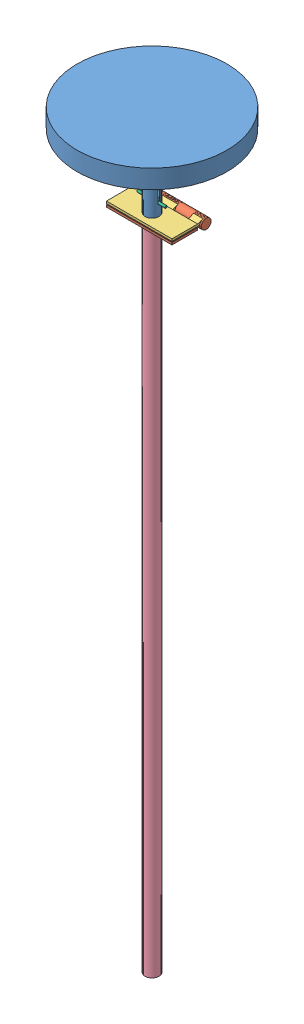
SolidWorks assembly Folding Steering Wheel, configuration Default. Lengths in mm.
Overall size (203.2 312.4 984.57).
6 component instances, 6 part files, 16 mates.
Components (placement in the parent):
- Mock Steering Wheel-1: Mock Steering Wheel [Default] at (27.4075 132.5013 163.5585)
- Door Hinge (2)-1: Door Hinge (2) [1494A11] at (27.4075 30.3171 136.571) x (-1 0 0) z (0 0 -1)
- Opposite Hinge-1: Opposite Hinge [Default] at (71.8575 30.3171 155.4226) x (0 0 -1) z (-1 0 0)
- Mock Steering Shaft-1: Mock Steering Shaft [Default] at (27.4075 -859.2671 163.5585) x (-0.950128 0 0.311862) z (-0.311862 0 -0.950128)
- Dowel-1: Dowel [Default] at (27.4075 8.6763 163.5585) x (1 0 0) z (0 1 0)
- Pull Pin-1: Pull Pin [Default] at (8.3575 49.9513 163.5585) x (1 0 0) z (0 0.325488 -0.945546)
Mates (geometry in assembly coordinates):
- Concentric2: concentric anti-aligned: cylinder of Door Hinge (2)-1 through (2.8414 30.3171 136.571) axis (-1 0 0) radius 6.7469; cylinder of Opposite Hinge-1 through (-17.0425 30.3171 136.571) axis (1 0 0) radius 3.3734
- Coincident9: coincident anti-aligned: circle of Door Hinge (2)-1; plane of Opposite Hinge-1 through (71.8575 30.3171 136.571) normal (1 0 0)
- Coincident10: coincident anti-aligned: circle of Mock Steering Wheel-1; circle of Opposite Hinge-1
- Parallel3: parallel aligned: plane of Opposite Hinge-1 through (71.8575 30.3171 136.571) normal (1 0 0)
- Coincident13: coincident anti-aligned: cylinder of Mock Steering Wheel-1 through (27.4075 119.8013 61.9585) axis (0 0 1) radius 2.3813; circle of 92620A544_Zinc Yellow-Chromate Plated Hex Head Screw-1
- Tangent1: tangent anti-aligned: cylinder of Mock Steering Wheel-1 through (27.4075 30.9013 163.5585) axis (0 1 0) radius 9.525; plane of 92620A544_Zinc Yellow-Chromate Plated Hex Head Screw-1 through (27.4075 94.4671 173.0835) normal (0 0 -1)
- Concentric3: concentric: cylinder of Mock Steering Wheel-1 through (27.4075 119.8013 61.9585) axis (0 0 1) radius 2.3813; circle of 92620A203_Zinc Yellow-Chromate Plated Hex Head Screw(1)-1
- Tangent2: tangent anti-aligned: cylinder of Mock Steering Wheel-1 through (27.4075 30.9013 163.5585) axis (0 1 0) radius 9.525; plane of 92620A203_Zinc Yellow-Chromate Plated Hex Head Screw(1)-1 through (31.9903 88.0513 173.0835) normal (0 0 -1)
- Concentric7: concentric anti-aligned: cylinder of Mock Steering Wheel-1 through (27.4075 30.9013 163.5585) axis (0 1 0) radius 8.636; cylinder of Dowel-1 through (27.4075 58.9854 163.5585) axis (0 -1 0) radius 8.509
- Concentric8: concentric aligned: cylinder of Dowel-1 through (75.0325 52.6354 163.5585) axis (-1 0 0) radius 1.5875; cylinder of Pull Pin-1 through (46.4575 52.6354 163.5585) axis (-1 0 0) radius 1.5875
- Distance1: distance = 19.05 mm anti-aligned: plane of Pull Pin-1 through (8.3575 52.6354 163.5585) normal (-1 0 0); plane of Dowel-1 through (27.4075 11.3604 163.5585) normal (1 0 0)
- Tangent4: tangent anti-aligned: plane of Mock Steering Wheel-1 through (53.3155 49.9513 161.971) normal (0 0 1); cylinder of Pull Pin-1 through (46.4575 52.6354 163.5585) axis (-1 0 0) radius 1.5875
- LimitDistance1: limit distance = 19.5409 mm: cylinder of Pull Pin-1 through (46.4575 52.6354 163.5585) axis (-1 0 0) radius 1.5875; cylinder of Mock Steering Wheel-1 through (53.3155 75.3513 163.5585) axis (-1 0 0) radius 1.5875
- LimitAngle1: limit planar angle = 1.893722 rad anti-aligned: plane of Opposite Hinge-1 through (-17.0425 30.9013 181.021) normal (0 -1 0); plane of Door Hinge (2)-1 through (-14.9078 -11.6499 121.9111) normal (0 -0.317343 0.948311)
- Coincident18: coincident aligned: circle of Door Hinge (2)-1; circle of Mock Steering Shaft-1
- Lock3: lock: unknown of Door Hinge (2)-1; unknown of Mock Steering Shaft-1
